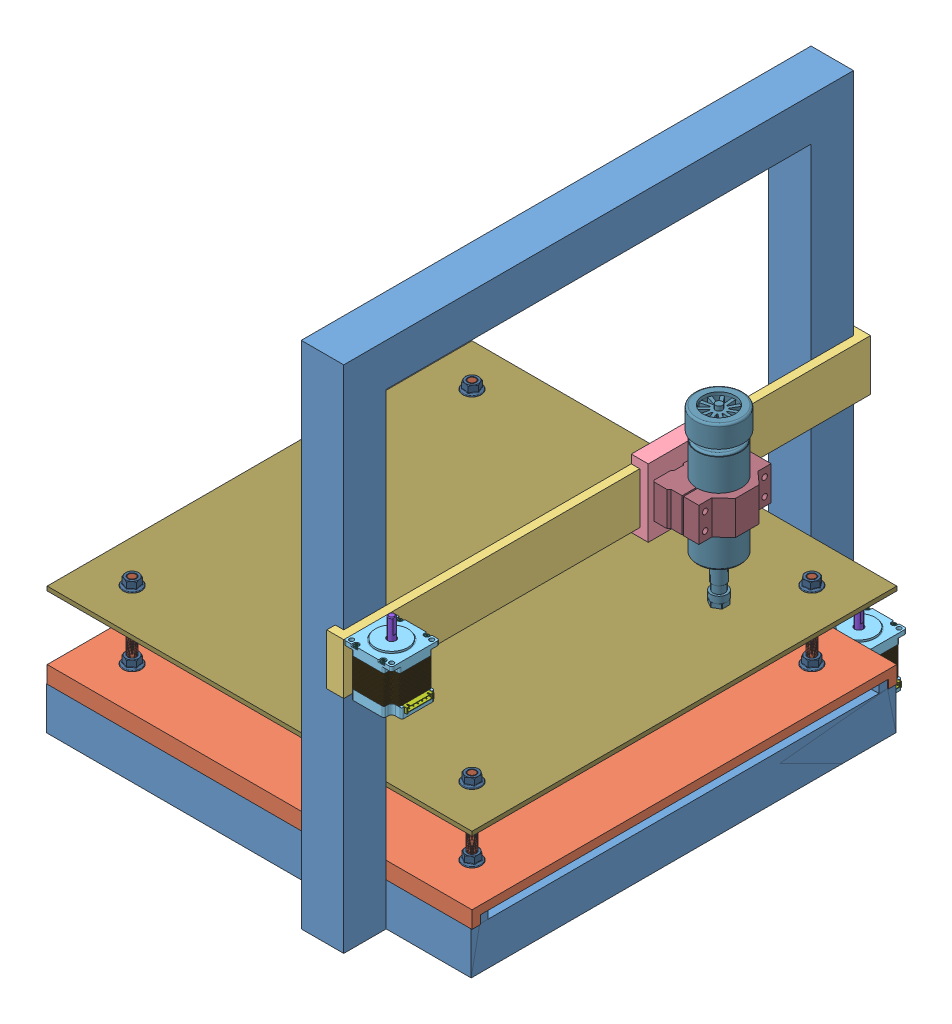
SolidWorks assembly Assembly, configuration Default. Lengths in mm.
Overall size (557.36 637.62 691.46).
46 component instances, 14 part files, 53 mates.
Components (placement in the parent):
- Part-1: Part [Default] at (-25 -351.9355 1082.8347) size (500 600 600)
- Part-2: Part [Default] at (-25 -351.9355 1082.8347) size (500 600 600)
- Part2-1: Part2 [Default] at (-24.043 -301.9355 1082.8347) x (0 0 1) z (0 1 0) size (500 500 20)
- Part1-1: Part1 [Default] at (115 -52.0855 1082.8347) x (0 0 -1) z (1 0 0) size (620 60 20)
- Part3-1: Part3 [Default] at (125 -52.0855 994.4292) x (0 1 0) z (1 0 0) size (80 100 20)
- motor nema 23-1: motor nema 23 [Default] at (153.2005 -295.5355 804.6337) x (1 0 -0.00005) z (0 -1 0) size (111.96 131.46 81.5)
  - 0-1: 0 [Default] at origin size (111.96 131.46 81.5)
    - 2-1: 2 [Default] at origin size (59.4 56.47 58)
    - 0_2-1: 0_2 [Default] at origin size (111.96 131.46 58.26)
    - 0_3-1: 0_3 [Default] at origin size (8 32 6.87)
    - 0_4-1: 0_4 [Default] at origin size (34 34 79)
    - 0_5-1: 0_5 [Default] at origin size (56.4 56.4 33.61)
- motor nema 23-5: motor nema 23 [Default] at (163.2 -22.0855 1364.6347) x (1 0 0) z (0 -1 0) size (111.96 131.46 81.5)
  - 0-1: 0 [Default] at origin size (111.96 131.46 81.5)
    - 2-1: 2 [Default] at origin size (59.4 56.47 58)
    - 0_2-1: 0_2 [Default] at origin size (111.96 131.46 58.26)
    - 0_3-1: 0_3 [Default] at origin size (8 32 6.87)
    - 0_4-1: 0_4 [Default] at origin size (34 34 79)
    - 0_5-1: 0_5 [Default] at origin size (56.4 56.4 33.61)
- motor nema 23-7: motor nema 23 [Default] at (-275 -323.7355 1082.8347) x (0 0 1) z (-1 0 0) size (111.96 131.46 81.5)
  - 0-1: 0 [Default] at origin size (111.96 131.46 81.5)
    - 2-1: 2 [Default] at origin size (59.4 56.47 58)
    - 0_2-1: 0_2 [Default] at origin size (111.96 131.46 58.26)
    - 0_3-1: 0_3 [Default] at origin size (8 32 6.87)
    - 0_4-1: 0_4 [Default] at origin size (34 34 79)
    - 0_5-1: 0_5 [Default] at origin size (56.4 56.4 33.61)
- hex flange nut gradea_iso-1: hex flange nut gradea_iso [Hexagon Flange Nut ISO - 4161 - M10 - S] at (175.957 -271.9355 1282.8347) x (1 0 0) z (0 1 0) size (21.8 21.8 10)
- hex flange bolt small_iso-1: hex flange bolt small_iso [ISO 4162 - M10 x 100 x 100-S] at (175.957 -301.6355 1282.8347) x (0 1 0) z (0 0 1) size (109.7 20.8 20.8)
- hex flange bolt small_iso-4: hex flange bolt small_iso [ISO 4162 - M10 x 100 x 100-S] at (175.957 -301.6355 882.8347) x (0 1 0) z (0.627871 0 -0.778317) size (109.7 20.8 20.8)
- hex flange bolt small_iso-5: hex flange bolt small_iso [ISO 4162 - M10 x 100 x 100-S] at (-224.043 -301.6355 1282.8347) x (0 1 0) z (0.395734 0 0.918365) size (109.7 20.8 20.8)
- hex flange bolt small_iso-6: hex flange bolt small_iso [ISO 4162 - M10 x 100 x 100-S] at (-224.043 -301.6355 882.8347) x (0 1 0) z (0.6 0 0.8) size (109.7 20.8 20.8)
- hex flange nut gradea_iso-4: hex flange nut gradea_iso [Hexagon Flange Nut ISO - 4161 - M10 - S] at (-224.043 -271.9355 1282.8347) x (0.982082 0 -0.188455) z (0 1 0) size (21.8 21.8 10)
- hex flange nut gradea_iso-5: hex flange nut gradea_iso [Hexagon Flange Nut ISO - 4161 - M10 - S] at (175.957 -271.9355 882.8347) x (0.918365 0 -0.395734) z (0 1 0) size (21.8 21.8 10)
- hex flange nut gradea_iso-6: hex flange nut gradea_iso [Hexagon Flange Nut ISO - 4161 - M10 - S] at (-224.043 -271.9355 882.8347) x (0.8 0 -0.6) z (0 1 0) size (21.8 21.8 10)
- hex flange nut gradea_iso-8: hex flange nut gradea_iso [Hexagon Flange Nut ISO - 4161 - M10 - S] at (175.957 -191.9355 1282.8347) x (1 0 0) z (0 1 0) size (21.8 21.8 10)
- hex flange nut gradea_iso-12: hex flange nut gradea_iso [Hexagon Flange Nut ISO - 4161 - M10 - S] at (175.957 -216.9355 1282.8347) x (1 0 0) z (0 -1 0) size (21.8 21.8 10)
- hex flange nut gradea_iso-13: hex flange nut gradea_iso [Hexagon Flange Nut ISO - 4161 - M10 - S] at (-224.043 -191.9355 1282.8347) x (0.982082 0 -0.188455) z (0 1 0) size (21.8 21.8 10)
- hex flange nut gradea_iso-14: hex flange nut gradea_iso [Hexagon Flange Nut ISO - 4161 - M10 - S] at (-224.043 -191.9355 882.8347) x (0.918365 0 -0.395734) z (0 1 0) size (21.8 21.8 10)
- hex flange nut gradea_iso-15: hex flange nut gradea_iso [Hexagon Flange Nut ISO - 4161 - M10 - S] at (175.957 -191.9355 882.8347) x (0.8 0 -0.6) z (0 1 0) size (21.8 21.8 10)
- hex flange nut gradea_iso-17: hex flange nut gradea_iso [Hexagon Flange Nut ISO - 4161 - M10 - S] at (175.957 -216.9355 882.8347) x (0.982082 0 -0.188455) z (0 -1 0) size (21.8 21.8 10)
- hex flange nut gradea_iso-18: hex flange nut gradea_iso [Hexagon Flange Nut ISO - 4161 - M10 - S] at (-224.043 -216.9355 882.8347) x (0.918365 0 -0.395734) z (0 -1 0) size (21.8 21.8 10)
- hex flange nut gradea_iso-19: hex flange nut gradea_iso [Hexagon Flange Nut ISO - 4161 - M10 - S] at (-224.043 -216.9355 1282.8347) x (0.8 0 -0.6) z (0 -1 0) size (21.8 21.8 10)
- Part4-1: Part4 [Default] at (-24.043 -206.9355 1082.8347) size (500 5 500)
- motor-1: motor [Default] at (84.9458 -79.9733 930.8384) x (0 0 1) z (-1 0 0) size (90 203.08 66.5)
  - Mount-1: Mount [Default] at (63.5908 7.8878 -93.3042) size (90 40 66.5)
  - SpindleFull-1: SpindleFull [Default] at (63.5908 54.6679 -93.3042) size (56.5 203.08 56.5)
Mates (geometry in assembly coordinates):
- Width3: width anti-aligned: plane of Part-1 through (-275 -291.9355 1312.8347) normal (0 0 -1); plane of Part-1 through (-275 -291.9355 852.8347) normal (0 0 1); plane of Part2-1 through (-274.043 -281.9355 1332.8347) normal (0 0 1); plane of Part2-1 through (-274.043 -281.9355 832.8347) normal (0 0 -1)
- Coincident3: coincident anti-aligned: plane of Part-1 through (-25 -301.9355 1082.8347) normal (0 1 0); plane of Part2-1 through (-24.043 -301.9355 1082.8347) normal (0 -1 0)
- Lock1: lock: unknown of ?
- Coincident36: coincident anti-aligned: plane of Part2-1 through (-274.043 -291.9355 842.8347) normal (0 -1 0); plane of hex flange bolt small_iso-1 through (168.4514 -291.9355 1282.8347) normal (0 1 0)
- Coincident37: coincident anti-aligned: cylinder of Part2-1 through (175.957 -291.9355 1282.8347) axis (0 1 0) radius 5; circle of hex flange bolt small_iso-1
- Coincident38: coincident anti-aligned: plane of Part2-1 through (-24.043 -281.9355 1082.8347) normal (0 1 0); plane of hex flange nut gradea_iso-1 through (175.957 -281.9355 1274.1744) normal (0 -1 0)
- Concentric1: concentric anti-aligned: circle of hex flange nut gradea_iso-1; circle of hex flange bolt small_iso-1
- Coincident42: coincident anti-aligned: plane of Part2-1 through (-274.043 -291.9355 842.8347) normal (0 -1 0); plane of hex flange bolt small_iso-4 through (181.7987 -291.9355 887.5472) normal (0 1 0)
- Concentric3: concentric anti-aligned: cylinder of Part2-1 through (175.957 -291.9355 882.8347) axis (0 1 0) radius 5; circle of hex flange bolt small_iso-4
- Coincident44: coincident anti-aligned: plane of Part2-1 through (-274.043 -291.9355 842.8347) normal (0 -1 0); plane of hex flange bolt small_iso-5 through (-230.9359 -291.9355 1285.8049) normal (0 1 0)
- Concentric4: concentric anti-aligned: cylinder of Part2-1 through (-224.043 -291.9355 1282.8347) axis (0 1 0) radius 5; circle of hex flange bolt small_iso-5
- Coincident45: coincident anti-aligned: plane of Part2-1 through (-274.043 -291.9355 842.8347) normal (0 -1 0); plane of hex flange bolt small_iso-6 through (-230.0475 -291.9355 887.338) normal (0 1 0)
- Concentric5: concentric anti-aligned: cylinder of Part2-1 through (-224.043 -291.9355 882.8347) axis (0 1 0) radius 5; circle of hex flange bolt small_iso-6
- Coincident48: coincident anti-aligned: plane of Part2-1 through (-24.043 -281.9355 1082.8347) normal (0 1 0); plane of hex flange nut gradea_iso-4 through (-225.6751 -281.9355 1274.3296) normal (0 -1 0)
- Concentric6: concentric anti-aligned: circle of hex flange bolt small_iso-5; circle of hex flange nut gradea_iso-4
- Coincident49: coincident anti-aligned: plane of Part2-1 through (-24.043 -281.9355 1082.8347) normal (0 1 0); plane of hex flange nut gradea_iso-5 through (172.5298 -281.9355 874.8814) normal (0 -1 0)
- Concentric7: concentric anti-aligned: circle of hex flange bolt small_iso-4; circle of hex flange nut gradea_iso-5
- Coincident50: coincident anti-aligned: plane of Part2-1 through (-24.043 -281.9355 1082.8347) normal (0 1 0); plane of hex flange nut gradea_iso-6 through (-229.2392 -281.9355 875.9065) normal (0 -1 0)
- Concentric8: concentric anti-aligned: circle of hex flange bolt small_iso-6; circle of hex flange nut gradea_iso-6
- Concentric9: concentric aligned: circle of hex flange bolt small_iso-1; circle of hex flange nut gradea_iso-8
- Coincident51: coincident aligned: plane of hex flange bolt small_iso-1 through (175.957 -191.9355 1282.8347) normal (0 1 0); plane of hex flange nut gradea_iso-8 through (175.957 -191.9355 1274.1744) normal (0 1 0)
- Distance1: distance = 5 mm anti-aligned: plane of hex flange nut gradea_iso-8 through (175.957 -201.9355 1274.1744) normal (0 -1 0); plane of hex flange nut gradea_iso-12 through (175.957 -206.9355 1291.4949) normal (0 1 0)
- Concentric10: concentric anti-aligned: circle of hex flange bolt small_iso-1; circle of hex flange nut gradea_iso-12
- Concentric11: concentric aligned: circle of hex flange bolt small_iso-5; circle of hex flange nut gradea_iso-13
- Coincident54: coincident aligned: plane of hex flange bolt small_iso-5 through (-224.043 -191.9355 1282.8347) normal (0 1 0); plane of hex flange nut gradea_iso-13 through (-225.6751 -191.9355 1274.3296) normal (0 1 0)
- Concentric12: concentric aligned: circle of hex flange bolt small_iso-6; circle of hex flange nut gradea_iso-14
- Coincident55: coincident aligned: plane of hex flange bolt small_iso-6 through (-224.043 -191.9355 882.8347) normal (0 1 0); plane of hex flange nut gradea_iso-14 through (-227.4702 -191.9355 874.8814) normal (0 1 0)
- Concentric13: concentric aligned: circle of hex flange bolt small_iso-4; circle of hex flange nut gradea_iso-15
- Coincident56: coincident aligned: plane of hex flange bolt small_iso-4 through (175.957 -191.9355 882.8347) normal (0 1 0); plane of hex flange nut gradea_iso-15 through (170.7608 -191.9355 875.9065) normal (0 1 0)
- Distance2: distance = 5 mm anti-aligned: plane of hex flange nut gradea_iso-15 through (170.7608 -201.9355 875.9065) normal (0 -1 0); plane of hex flange nut gradea_iso-17 through (177.589 -206.9355 891.3398) normal (0 1 0)
- Concentric14: concentric anti-aligned: circle of hex flange bolt small_iso-4; circle of hex flange nut gradea_iso-17
- Distance3: distance = 5 mm anti-aligned: plane of hex flange nut gradea_iso-14 through (-227.4702 -201.9355 874.8814) normal (0 -1 0); plane of hex flange nut gradea_iso-18 through (-220.6159 -206.9355 890.788) normal (0 1 0)
- Concentric15: concentric anti-aligned: circle of hex flange bolt small_iso-6; circle of hex flange nut gradea_iso-18
- Distance4: distance = 5 mm anti-aligned: plane of hex flange nut gradea_iso-13 through (-225.6751 -201.9355 1274.3296) normal (0 -1 0); plane of hex flange nut gradea_iso-19 through (-218.8469 -206.9355 1289.7629) normal (0 1 0)
- Concentric16: concentric anti-aligned: circle of hex flange bolt small_iso-5; circle of hex flange nut gradea_iso-19
- Concentric17: concentric anti-aligned: circle of hex flange bolt small_iso-6; circle of Part4-1
- Concentric18: concentric anti-aligned: circle of hex flange bolt small_iso-1; circle of Part4-1
- Coincident59: coincident anti-aligned: plane of hex flange nut gradea_iso-17 through (177.589 -206.9355 891.3398) normal (0 1 0); plane of Part4-1 through (-24.043 -206.9355 1082.8347) normal (0 -1 0)
- Coincident60: coincident anti-aligned: plane of Part3-1 through (145 -52.0855 994.4292) normal (1 0 0); plane of motor-1/Mount-1 through (145 -32.0855 1003.4292) normal (-1 0 0)
- Width5: width aligned: plane of Part3-1 through (145 -92.0855 1044.4292) normal (0 -1 0); plane of Part3-1 through (145 -12.0855 1044.4292) normal (0 1 0); plane of motor-1/Mount-1 through (178.25 -72.0855 994.4292) normal (0 -1 0); plane of motor-1/Mount-1 through (178.25 -32.0855 994.4292) normal (0 1 0)
- Width6: width aligned: plane of Part3-1 through (145 -92.0855 1044.4292) normal (0 0 1); plane of Part3-1 through (145 -92.0855 944.4292) normal (0 0 -1); plane of motor-1/Mount-1 through (197 -32.0855 1036.9292) normal (0 0 1); plane of motor-1/Mount-1 through (197 -32.0855 951.9292) normal (0 0 -1)
- Coincident64: coincident anti-aligned: plane of Part-1 through (-275 -301.9355 832.8347) normal (0 0 -1); plane of motor nema 23-1/0-1/2-1 through (153.2022 -340.4355 832.8347) normal (0 0 1)
- Coincident61: coincident aligned: plane of Part-1 through (-25 -351.9355 1082.8347) normal (0 -1 0); plane of motor nema 23-1/0-1/2-1 through (153.2005 -351.9355 804.6337) normal (0 -1 0)
- Distance8: distance = 0 mm: line of motor nema 23-1/0-1/2-1 through (125.0013 -351.9355 821.7353) axis (-0.00005 0 -1); line of Part-2 through (125 -351.9355 782.8347) axis (0 0 1)
- Coincident84: coincident anti-aligned: plane of motor nema 23-7/0-1/2-1 through (-275 -323.7355 1082.8347) normal (1 0 0); plane of Part-1 through (-275 -301.9355 1332.8347) normal (-1 0 0)
- Width8: width aligned: plane of Part-1 through (-275 -301.9355 1332.8347) normal (0 0 1); plane of Part-1 through (-275 -301.9355 832.8347) normal (0 0 -1); plane of ? through (-286.5 -323.7355 1111.0347) normal (0 0 1); plane of ? through (-286.5 -323.7355 1054.6347) normal (0 0 -1)
- Coincident92: coincident aligned: plane of Part1-1 through (135 -82.0855 1392.8347) normal (0 0 1); plane of motor nema 23-5/0-1/2-1 through (163.2 -33.5855 1392.8347) normal (0 0 1)
- Coincident93: coincident aligned: plane of Part1-1 through (135 -22.0855 1392.8347) normal (0 1 0); plane of ? through (163.2 -22.0855 1364.6347) normal (0 1 0)
- Coincident94: coincident anti-aligned: plane of Part1-1 through (135 -52.0855 1082.8347) normal (1 0 0); plane of ? through (135 -33.5855 1364.6347) normal (-1 0 0)
- Coincident95: coincident anti-aligned: plane of Part-1 through (75 198.0645 782.8347) normal (0 0 -1); plane of Part1-1 through (115 -122.0855 782.8347) normal (0 0 1)
- Coincident100: coincident anti-aligned: plane of Part-1 through (125 198.0645 832.8347) normal (1 0 0); plane of Part1-1 through (125 -122.0855 1382.8347) normal (-1 0 0)
- Coincident101: coincident anti-aligned: plane of Part1-1 through (135 -52.0855 1082.8347) normal (1 0 0); plane of Part3-1 through (135 -82.0855 944.4292) normal (-1 0 0)
- Width9: width aligned: plane of Part3-1 through (125 -82.0855 944.4292) normal (0 1 0); plane of Part3-1 through (125 -22.0855 944.4292) normal (0 -1 0); plane of Part1-1 through (135 -22.0855 1392.8347) normal (0 1 0); plane of Part1-1 through (135 -82.0855 1392.8347) normal (0 -1 0)
